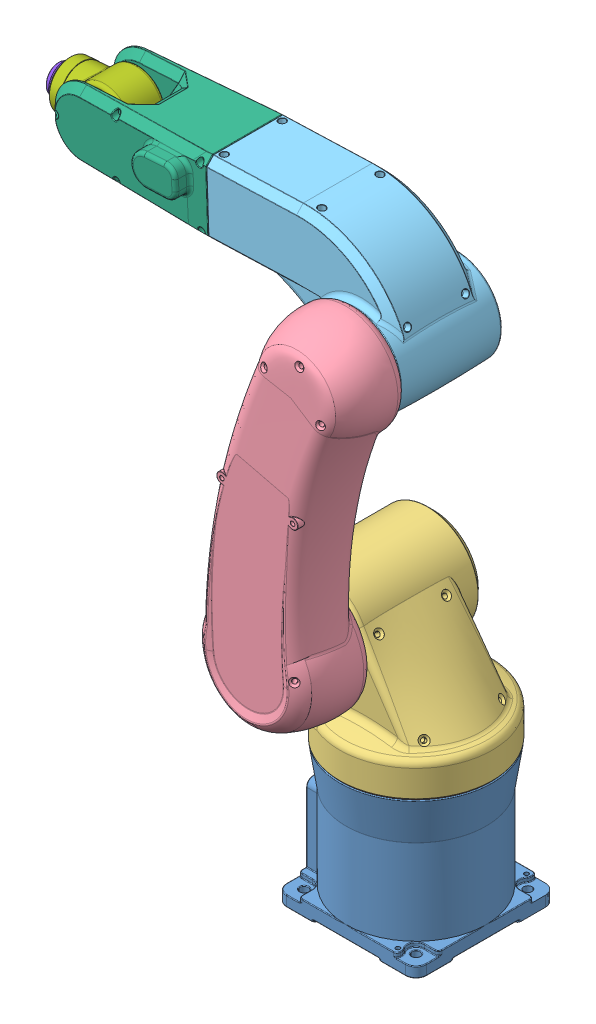
SolidWorks assembly KUKA KR-5 R850, configuration Default. Lengths in mm.
Overall size (671.59 837.88 318.81).
8 component instances, 8 part files, 25 mates.
Components (placement in the parent):
- Base-1: Base [Default] at origin size (237.61 207 217.22)
- Base Motor Cover A-1: Base Motor Cover A [Default] at (0 188 0) x (0.866025 0 0.5) z (-0.5 0 0.866025) size (214.61 15 214.61)
- 1st Axis Arm-1: 1st Axis Arm [Default] at (0 202.9996 0) x (-1 0 0) z (0 0 -1) size (256.5 252.5 218)
- 2nd Axis Arm-1: 2nd Axis Arm [Default] at (-75 332.9996 106.5) x (0.997086 0.076288 0) z (0.076288 -0.997086 0) size (245.77 148.73 517.88)
- 3rd Axis Arm-1: 3rd Axis Arm [Default] at (-19.0879 693.6918 -1) x (0 0 -1) z (0.999418 0.034125 0) size (150 208.5 284.5)
- 4th Axis Arm-1: 4th Axis Arm [Default] at (-240.0322 776.2 -1) x (-0.999418 -0.034125 0) z (0 0 -1) size (254.77 122.8 152)
- 5th Axis Arm-1: 5th Axis Arm [Default] at (-425.9238 769.8527 -2) x (-0.090851 0.995865 0) z (0.995865 0.090851 0) size (80 66 114)
- 6th Axis Arm-1: 6th Axis Arm [Default] at (-499.6178 763.1298 -2) x (-0.084729 0.928761 -0.360864) z (-0.032785 0.359372 0.932618) size (49 39.58 49)
Mates (geometry in assembly coordinates):
- Eş Merkezli1: concentric anti-aligned: cylinder of Base Motor Cover A-1 through (0 188 0) axis (0 -1 0) radius 50; cylinder of 1st Axis Arm-1 through (0 153 0) axis (0 1 0) radius 47.5
- Çakışık1: coincident anti-aligned: plane of Base Motor Cover A-1 through (68.849 203 39.75) normal (0 1 0); plane of 1st Axis Arm-1 through (-108.95 203 4.6008) normal (0 -1 0)
- Eş Merkezli2: concentric aligned: cylinder of 1st Axis Arm-1 through (-75 332.9996 23.5) axis (0 0 1) radius 37.5; cylinder of 2nd Axis Arm-1 through (-75 332.9996 23.5) axis (0 0 1) radius 35.5
- Çakışık2: coincident anti-aligned: plane of 1st Axis Arm-1 through (-143.9907 216.0879 73.5) normal (0 0 1); plane of 2nd Axis Arm-1 through (-75 332.9996 73.5) normal (0 0 -1)
- Eş Merkezli3: concentric anti-aligned: cylinder of 2nd Axis Arm-1 through (-19.0879 693.6918 38) axis (0 0 1) radius 25; cylinder of 3rd Axis Arm-1 through (-19.0879 693.6918 68) axis (0 0 -1) radius 25
- Çakışık3: coincident anti-aligned: plane of 2nd Axis Arm-1 through (-19.0879 693.6918 68) normal (0 0 -1); plane of 3rd Axis Arm-1 through (-19.0879 693.6918 68) normal (0 0 1)
- Eş Merkezli4: concentric aligned: cylinder of 3rd Axis Arm-1 through (-220.0438 776.8826 -1) axis (-0.999418 -0.034125 0) radius 30; cylinder of 4th Axis Arm-1 through (-220.0438 776.8826 -1) axis (-0.999418 -0.034125 0) radius 27.5
- Çakışık4: coincident anti-aligned: plane of 3rd Axis Arm-1 through (-239.159 750.6281 -60.5) normal (-0.999418 -0.034125 0); plane of 4th Axis Arm-1 through (-233.2141 576.5221 -60.5) normal (0.999418 0.034125 0)
- Eş Merkezli5: concentric anti-aligned: cone of Base-1 through (0 188 0) axis (0 -1 0); cylinder of 1st Axis Arm-1 through (0 153 0) axis (0 1 0) radius 47.5
- Çakışık5: coincident aligned: cylinder of Base-1 through (0 203 0) axis (0 -1 0) radius 859.8431; cylinder of Base Motor Cover A-1 through (0 188 0) axis (0 -1 0) radius 859.8431
- Eş Merkezli6: concentric aligned: cylinder of 4th Axis Arm-1 through (-425.9238 769.8527 -60.2843) axis (0 0 1) radius 10; cylinder of 5th Axis Arm-1 through (-425.9238 769.8527 -57.2843) axis (0 0 1) radius 10
- Uzaklık2: distance = 5 mm anti-aligned: plane of 5th Axis Arm-1 through (-425.9238 769.8527 25) normal (0 0 1); plane of 4th Axis Arm-1 through (-350.4812 572.518 30) normal (0 0 -1)
- Eş Merkezli7: concentric aligned: cylinder of 5th Axis Arm-1 through (-497.6261 763.3115 -2) axis (0.995865 0.090851 0) radius 24.5; cylinder of 6th Axis Arm-1 through (-503.1033 762.8118 -2) axis (0.995865 0.090851 0) radius 10
- Çakışık8: coincident anti-aligned: plane of 5th Axis Arm-1 through (-499.6178 763.1298 -2) normal (-0.995865 -0.090851 0); plane of 6th Axis Arm-1 through (-499.6178 763.1298 -2) normal (0.995865 0.090851 0)
- Paralel1: parallel: plane of assembly through (0 0 0) normal (1 0 0); plane of Base-1 through (-100 15 -85) normal (-1 0 0); plane of assembly
- Eş Merkezli8: concentric aligned: cylinder of Base-1 through (-117.5 207 0) axis (0 -1 0) radius 7; cylinder of 1st Axis Arm-1 through (-117.5 202.9996 0) axis (0 -1 0) radius 4.5
- Paralel2: parallel aligned: unknown of 3rd Axis Arm-1
- Paralel7: parallel anti-aligned: line of 3rd Axis Arm-1 through (-208.7344 830.3753 -50.0858) axis (0 0 1); line of 4th Axis Arm-1 through (-210.7522 830.3571 48.0858) axis (0 0 -1)
- Paralel8: parallel anti-aligned: plane of 6th Axis Arm-1 through (-481.7344 778.3753 -2) normal (-1 0 0)
- Paralel10: parallel: line of 2nd Axis Arm-1 through (-356.4919 332.9996 254.6461) axis (1 0 0)
- Kilitle1: lock: unknown of Base-1; unknown of 1st Axis Arm-1
- Kilitle2: lock: unknown of 2nd Axis Arm-1; unknown of 3rd Axis Arm-1
- Kilitle3: lock: unknown of 3rd Axis Arm-1; unknown of 4th Axis Arm-1
- Kilitle4: lock: unknown of 4th Axis Arm-1; unknown of 5th Axis Arm-1
- Kilitle5: lock: unknown of 5th Axis Arm-1; unknown of 6th Axis Arm-1
